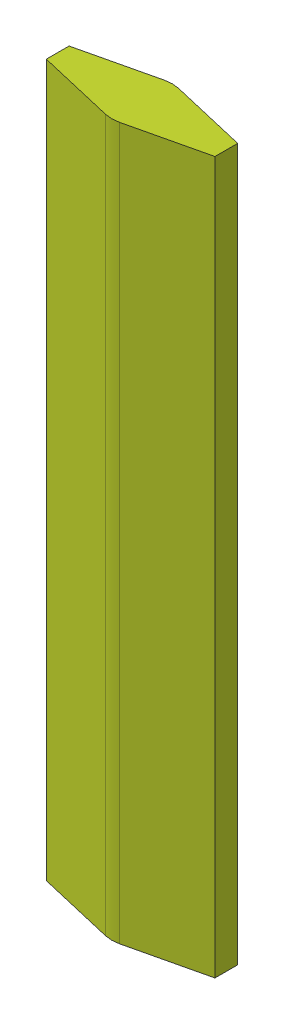
SolidWorks assembly RealString, configuration 默认. Lengths in mm.
Overall size (400 1620 359.66).
221 component instances, 7 part files, 3 mates.
Components (placement in the parent):
- RealUnit-1: RealUnit [默认] at (122.5675 -142.7262 804.774) size (400 106.44 359.66)
  - OuterShell-III-Part-6: OuterShell-III-Part [默认] at (-118.393 127.2935 -404.774) size (400 73.59 241.95)
  - OuterShell-III-Part-7: OuterShell-III-Part [默认] at (-118.393 127.2935 -404.774) x (-1 0 0) z (0 0 -1) size (400 73.59 241.95)
  - ConnectionRod-5: ConnectionRod [默认] at (-290.393 189.5608 -404.774) size (22.09 84 14)
  - ConnectionRod-9: ConnectionRod [默认] at (53.607 189.5608 -404.774) x (-1 0 0) z (0 0 -1) size (22.09 84 14)
  - InnerUnit-2: InnerUnit [默认] at (-116.4448 157.913 -484.774) x (-1 0 0) z (0 0 1) size (102 85 103.7)
    - BEGeDet-2: BEGeDet [默认] at (1.9481 14.6195 80) x (1 0 0) z (0 0 -1) size (80 40 80)
    - InnerShell-3: InnerShell [默认] at (1.9481 -36.3805 80) size (102 61 102)
    - Electronics-1: Electronics [默认] at (1.9481 24.7195 80) x (-1 0 0) z (0 0 1) size (21.21 85 103.7)
  - SiPMArray-1: SiPMArray [默认] at (46.607 162.6183 -404.774) size (10.4 81 40.4)
  - SiPMArray-2: SiPMArray [默认] at (-283.393 162.6183 -404.774) x (-1 0 0) z (0 0 -1) size (10.4 81 40.4)
- RealUnit-3: RealUnit [默认] at (122.5675 -66.7262 804.774) size (400 106.44 359.66)
  - OuterShell-III-Part-6: OuterShell-III-Part [默认] at (-118.393 127.2935 -404.774) size (400 73.59 241.95)
  - OuterShell-III-Part-7: OuterShell-III-Part [默认] at (-118.393 127.2935 -404.774) x (-1 0 0) z (0 0 -1) size (400 73.59 241.95)
  - ConnectionRod-5: ConnectionRod [默认] at (-290.393 189.5608 -404.774) size (22.09 84 14)
  - ConnectionRod-9: ConnectionRod [默认] at (53.607 189.5608 -404.774) x (-1 0 0) z (0 0 -1) size (22.09 84 14)
  - InnerUnit-2: InnerUnit [默认] at (-116.4448 157.913 -484.774) x (-1 0 0) z (0 0 1) size (102 85 103.7)
    - BEGeDet-2: BEGeDet [默认] at (1.9481 14.6195 80) x (1 0 0) z (0 0 -1) size (80 40 80)
    - InnerShell-3: InnerShell [默认] at (1.9481 -36.3805 80) size (102 61 102)
    - Electronics-1: Electronics [默认] at (1.9481 24.7195 80) x (-1 0 0) z (0 0 1) size (21.21 85 103.7)
  - SiPMArray-1: SiPMArray [默认] at (46.607 162.6183 -404.774) size (10.4 81 40.4)
  - SiPMArray-2: SiPMArray [默认] at (-283.393 162.6183 -404.774) x (-1 0 0) z (0 0 -1) size (10.4 81 40.4)
- RealUnit-22: RealUnit [默认] at (122.5675 9.2738 804.774) size (400 106.44 359.66)
  - OuterShell-III-Part-6: OuterShell-III-Part [默认] at (-118.393 127.2935 -404.774) size (400 73.59 241.95)
  - OuterShell-III-Part-7: OuterShell-III-Part [默认] at (-118.393 127.2935 -404.774) x (-1 0 0) z (0 0 -1) size (400 73.59 241.95)
  - ConnectionRod-5: ConnectionRod [默认] at (-290.393 189.5608 -404.774) size (22.09 84 14)
  - ConnectionRod-9: ConnectionRod [默认] at (53.607 189.5608 -404.774) x (-1 0 0) z (0 0 -1) size (22.09 84 14)
  - InnerUnit-2: InnerUnit [默认] at (-116.4448 157.913 -484.774) x (-1 0 0) z (0 0 1) size (102 85 103.7)
    - BEGeDet-2: BEGeDet [默认] at (1.9481 14.6195 80) x (1 0 0) z (0 0 -1) size (80 40 80)
    - InnerShell-3: InnerShell [默认] at (1.9481 -36.3805 80) size (102 61 102)
    - Electronics-1: Electronics [默认] at (1.9481 24.7195 80) x (-1 0 0) z (0 0 1) size (21.21 85 103.7)
  - SiPMArray-1: SiPMArray [默认] at (46.607 162.6183 -404.774) size (10.4 81 40.4)
  - SiPMArray-2: SiPMArray [默认] at (-283.393 162.6183 -404.774) x (-1 0 0) z (0 0 -1) size (10.4 81 40.4)
- RealUnit-23: RealUnit [默认] at (122.5675 85.2738 804.774) size (400 106.44 359.66)
  - OuterShell-III-Part-6: OuterShell-III-Part [默认] at (-118.393 127.2935 -404.774) size (400 73.59 241.95)
  - OuterShell-III-Part-7: OuterShell-III-Part [默认] at (-118.393 127.2935 -404.774) x (-1 0 0) z (0 0 -1) size (400 73.59 241.95)
  - ConnectionRod-5: ConnectionRod [默认] at (-290.393 189.5608 -404.774) size (22.09 84 14)
  - ConnectionRod-9: ConnectionRod [默认] at (53.607 189.5608 -404.774) x (-1 0 0) z (0 0 -1) size (22.09 84 14)
  - InnerUnit-2: InnerUnit [默认] at (-116.4448 157.913 -484.774) x (-1 0 0) z (0 0 1) size (102 85 103.7)
    - BEGeDet-2: BEGeDet [默认] at (1.9481 14.6195 80) x (1 0 0) z (0 0 -1) size (80 40 80)
    - InnerShell-3: InnerShell [默认] at (1.9481 -36.3805 80) size (102 61 102)
    - Electronics-1: Electronics [默认] at (1.9481 24.7195 80) x (-1 0 0) z (0 0 1) size (21.21 85 103.7)
  - SiPMArray-1: SiPMArray [默认] at (46.607 162.6183 -404.774) size (10.4 81 40.4)
  - SiPMArray-2: SiPMArray [默认] at (-283.393 162.6183 -404.774) x (-1 0 0) z (0 0 -1) size (10.4 81 40.4)
- RealUnit-24: RealUnit [默认] at (122.5675 161.2738 804.774) size (400 106.44 359.66)
  - OuterShell-III-Part-6: OuterShell-III-Part [默认] at (-118.393 127.2935 -404.774) size (400 73.59 241.95)
  - OuterShell-III-Part-7: OuterShell-III-Part [默认] at (-118.393 127.2935 -404.774) x (-1 0 0) z (0 0 -1) size (400 73.59 241.95)
  - ConnectionRod-5: ConnectionRod [默认] at (-290.393 189.5608 -404.774) size (22.09 84 14)
  - ConnectionRod-9: ConnectionRod [默认] at (53.607 189.5608 -404.774) x (-1 0 0) z (0 0 -1) size (22.09 84 14)
  - InnerUnit-2: InnerUnit [默认] at (-116.4448 157.913 -484.774) x (-1 0 0) z (0 0 1) size (102 85 103.7)
    - BEGeDet-2: BEGeDet [默认] at (1.9481 14.6195 80) x (1 0 0) z (0 0 -1) size (80 40 80)
    - InnerShell-3: InnerShell [默认] at (1.9481 -36.3805 80) size (102 61 102)
    - Electronics-1: Electronics [默认] at (1.9481 24.7195 80) x (-1 0 0) z (0 0 1) size (21.21 85 103.7)
  - SiPMArray-1: SiPMArray [默认] at (46.607 162.6183 -404.774) size (10.4 81 40.4)
  - SiPMArray-2: SiPMArray [默认] at (-283.393 162.6183 -404.774) x (-1 0 0) z (0 0 -1) size (10.4 81 40.4)
- RealUnit-25: RealUnit [默认] at (122.5675 237.2738 804.774) size (400 106.44 359.66)
  - OuterShell-III-Part-6: OuterShell-III-Part [默认] at (-118.393 127.2935 -404.774) size (400 73.59 241.95)
  - OuterShell-III-Part-7: OuterShell-III-Part [默认] at (-118.393 127.2935 -404.774) x (-1 0 0) z (0 0 -1) size (400 73.59 241.95)
  - ConnectionRod-5: ConnectionRod [默认] at (-290.393 189.5608 -404.774) size (22.09 84 14)
  - ConnectionRod-9: ConnectionRod [默认] at (53.607 189.5608 -404.774) x (-1 0 0) z (0 0 -1) size (22.09 84 14)
  - InnerUnit-2: InnerUnit [默认] at (-116.4448 157.913 -484.774) x (-1 0 0) z (0 0 1) size (102 85 103.7)
    - BEGeDet-2: BEGeDet [默认] at (1.9481 14.6195 80) x (1 0 0) z (0 0 -1) size (80 40 80)
    - InnerShell-3: InnerShell [默认] at (1.9481 -36.3805 80) size (102 61 102)
    - Electronics-1: Electronics [默认] at (1.9481 24.7195 80) x (-1 0 0) z (0 0 1) size (21.21 85 103.7)
  - SiPMArray-1: SiPMArray [默认] at (46.607 162.6183 -404.774) size (10.4 81 40.4)
  - SiPMArray-2: SiPMArray [默认] at (-283.393 162.6183 -404.774) x (-1 0 0) z (0 0 -1) size (10.4 81 40.4)
- RealUnit-26: RealUnit [默认] at (122.5675 313.2738 804.774) size (400 106.44 359.66)
  - OuterShell-III-Part-6: OuterShell-III-Part [默认] at (-118.393 127.2935 -404.774) size (400 73.59 241.95)
  - OuterShell-III-Part-7: OuterShell-III-Part [默认] at (-118.393 127.2935 -404.774) x (-1 0 0) z (0 0 -1) size (400 73.59 241.95)
  - ConnectionRod-5: ConnectionRod [默认] at (-290.393 189.5608 -404.774) size (22.09 84 14)
  - ConnectionRod-9: ConnectionRod [默认] at (53.607 189.5608 -404.774) x (-1 0 0) z (0 0 -1) size (22.09 84 14)
  - InnerUnit-2: InnerUnit [默认] at (-116.4448 157.913 -484.774) x (-1 0 0) z (0 0 1) size (102 85 103.7)
    - BEGeDet-2: BEGeDet [默认] at (1.9481 14.6195 80) x (1 0 0) z (0 0 -1) size (80 40 80)
    - InnerShell-3: InnerShell [默认] at (1.9481 -36.3805 80) size (102 61 102)
    - Electronics-1: Electronics [默认] at (1.9481 24.7195 80) x (-1 0 0) z (0 0 1) size (21.21 85 103.7)
  - SiPMArray-1: SiPMArray [默认] at (46.607 162.6183 -404.774) size (10.4 81 40.4)
  - SiPMArray-2: SiPMArray [默认] at (-283.393 162.6183 -404.774) x (-1 0 0) z (0 0 -1) size (10.4 81 40.4)
- RealUnit-27: RealUnit [默认] at (122.5675 389.2738 804.774) size (400 106.44 359.66)
  - OuterShell-III-Part-6: OuterShell-III-Part [默认] at (-118.393 127.2935 -404.774) size (400 73.59 241.95)
  - OuterShell-III-Part-7: OuterShell-III-Part [默认] at (-118.393 127.2935 -404.774) x (-1 0 0) z (0 0 -1) size (400 73.59 241.95)
  - ConnectionRod-5: ConnectionRod [默认] at (-290.393 189.5608 -404.774) size (22.09 84 14)
  - ConnectionRod-9: ConnectionRod [默认] at (53.607 189.5608 -404.774) x (-1 0 0) z (0 0 -1) size (22.09 84 14)
  - InnerUnit-2: InnerUnit [默认] at (-116.4448 157.913 -484.774) x (-1 0 0) z (0 0 1) size (102 85 103.7)
    - BEGeDet-2: BEGeDet [默认] at (1.9481 14.6195 80) x (1 0 0) z (0 0 -1) size (80 40 80)
    - InnerShell-3: InnerShell [默认] at (1.9481 -36.3805 80) size (102 61 102)
    - Electronics-1: Electronics [默认] at (1.9481 24.7195 80) x (-1 0 0) z (0 0 1) size (21.21 85 103.7)
  - SiPMArray-1: SiPMArray [默认] at (46.607 162.6183 -404.774) size (10.4 81 40.4)
  - SiPMArray-2: SiPMArray [默认] at (-283.393 162.6183 -404.774) x (-1 0 0) z (0 0 -1) size (10.4 81 40.4)
- RealUnit-28: RealUnit [默认] at (122.5675 465.2738 804.774) size (400 106.44 359.66)
  - OuterShell-III-Part-6: OuterShell-III-Part [默认] at (-118.393 127.2935 -404.774) size (400 73.59 241.95)
  - OuterShell-III-Part-7: OuterShell-III-Part [默认] at (-118.393 127.2935 -404.774) x (-1 0 0) z (0 0 -1) size (400 73.59 241.95)
  - ConnectionRod-5: ConnectionRod [默认] at (-290.393 189.5608 -404.774) size (22.09 84 14)
  - ConnectionRod-9: ConnectionRod [默认] at (53.607 189.5608 -404.774) x (-1 0 0) z (0 0 -1) size (22.09 84 14)
  - InnerUnit-2: InnerUnit [默认] at (-116.4448 157.913 -484.774) x (-1 0 0) z (0 0 1) size (102 85 103.7)
    - BEGeDet-2: BEGeDet [默认] at (1.9481 14.6195 80) x (1 0 0) z (0 0 -1) size (80 40 80)
    - InnerShell-3: InnerShell [默认] at (1.9481 -36.3805 80) size (102 61 102)
    - Electronics-1: Electronics [默认] at (1.9481 24.7195 80) x (-1 0 0) z (0 0 1) size (21.21 85 103.7)
  - SiPMArray-1: SiPMArray [默认] at (46.607 162.6183 -404.774) size (10.4 81 40.4)
  - SiPMArray-2: SiPMArray [默认] at (-283.393 162.6183 -404.774) x (-1 0 0) z (0 0 -1) size (10.4 81 40.4)
- RealUnit-29: RealUnit [默认] at (122.5675 541.2738 804.774) size (400 106.44 359.66)
  - OuterShell-III-Part-6: OuterShell-III-Part [默认] at (-118.393 127.2935 -404.774) size (400 73.59 241.95)
  - OuterShell-III-Part-7: OuterShell-III-Part [默认] at (-118.393 127.2935 -404.774) x (-1 0 0) z (0 0 -1) size (400 73.59 241.95)
  - ConnectionRod-5: ConnectionRod [默认] at (-290.393 189.5608 -404.774) size (22.09 84 14)
  - ConnectionRod-9: ConnectionRod [默认] at (53.607 189.5608 -404.774) x (-1 0 0) z (0 0 -1) size (22.09 84 14)
  - InnerUnit-2: InnerUnit [默认] at (-116.4448 157.913 -484.774) x (-1 0 0) z (0 0 1) size (102 85 103.7)
    - BEGeDet-2: BEGeDet [默认] at (1.9481 14.6195 80) x (1 0 0) z (0 0 -1) size (80 40 80)
    - InnerShell-3: InnerShell [默认] at (1.9481 -36.3805 80) size (102 61 102)
    - Electronics-1: Electronics [默认] at (1.9481 24.7195 80) x (-1 0 0) z (0 0 1) size (21.21 85 103.7)
  - SiPMArray-1: SiPMArray [默认] at (46.607 162.6183 -404.774) size (10.4 81 40.4)
  - SiPMArray-2: SiPMArray [默认] at (-283.393 162.6183 -404.774) x (-1 0 0) z (0 0 -1) size (10.4 81 40.4)
- RealUnit-30: RealUnit [默认] at (122.5675 617.2738 804.774) size (400 106.44 359.66)
  - OuterShell-III-Part-6: OuterShell-III-Part [默认] at (-118.393 127.2935 -404.774) size (400 73.59 241.95)
  - OuterShell-III-Part-7: OuterShell-III-Part [默认] at (-118.393 127.2935 -404.774) x (-1 0 0) z (0 0 -1) size (400 73.59 241.95)
  - ConnectionRod-5: ConnectionRod [默认] at (-290.393 189.5608 -404.774) size (22.09 84 14)
  - ConnectionRod-9: ConnectionRod [默认] at (53.607 189.5608 -404.774) x (-1 0 0) z (0 0 -1) size (22.09 84 14)
  - InnerUnit-2: InnerUnit [默认] at (-116.4448 157.913 -484.774) x (-1 0 0) z (0 0 1) size (102 85 103.7)
    - BEGeDet-2: BEGeDet [默认] at (1.9481 14.6195 80) x (1 0 0) z (0 0 -1) size (80 40 80)
    - InnerShell-3: InnerShell [默认] at (1.9481 -36.3805 80) size (102 61 102)
    - Electronics-1: Electronics [默认] at (1.9481 24.7195 80) x (-1 0 0) z (0 0 1) size (21.21 85 103.7)
  - SiPMArray-1: SiPMArray [默认] at (46.607 162.6183 -404.774) size (10.4 81 40.4)
  - SiPMArray-2: SiPMArray [默认] at (-283.393 162.6183 -404.774) x (-1 0 0) z (0 0 -1) size (10.4 81 40.4)
- RealUnit-31: RealUnit [默认] at (122.5675 693.2738 804.774) size (400 106.44 359.66)
  - OuterShell-III-Part-6: OuterShell-III-Part [默认] at (-118.393 127.2935 -404.774) size (400 73.59 241.95)
  - OuterShell-III-Part-7: OuterShell-III-Part [默认] at (-118.393 127.2935 -404.774) x (-1 0 0) z (0 0 -1) size (400 73.59 241.95)
  - ConnectionRod-5: ConnectionRod [默认] at (-290.393 189.5608 -404.774) size (22.09 84 14)
  - ConnectionRod-9: ConnectionRod [默认] at (53.607 189.5608 -404.774) x (-1 0 0) z (0 0 -1) size (22.09 84 14)
  - InnerUnit-2: InnerUnit [默认] at (-116.4448 157.913 -484.774) x (-1 0 0) z (0 0 1) size (102 85 103.7)
    - BEGeDet-2: BEGeDet [默认] at (1.9481 14.6195 80) x (1 0 0) z (0 0 -1) size (80 40 80)
    - InnerShell-3: InnerShell [默认] at (1.9481 -36.3805 80) size (102 61 102)
    - Electronics-1: Electronics [默认] at (1.9481 24.7195 80) x (-1 0 0) z (0 0 1) size (21.21 85 103.7)
  - SiPMArray-1: SiPMArray [默认] at (46.607 162.6183 -404.774) size (10.4 81 40.4)
  - SiPMArray-2: SiPMArray [默认] at (-283.393 162.6183 -404.774) x (-1 0 0) z (0 0 -1) size (10.4 81 40.4)
- RealUnit-32: RealUnit [默认] at (122.5675 769.2738 804.774) size (400 106.44 359.66)
  - OuterShell-III-Part-6: OuterShell-III-Part [默认] at (-118.393 127.2935 -404.774) size (400 73.59 241.95)
  - OuterShell-III-Part-7: OuterShell-III-Part [默认] at (-118.393 127.2935 -404.774) x (-1 0 0) z (0 0 -1) size (400 73.59 241.95)
  - ConnectionRod-5: ConnectionRod [默认] at (-290.393 189.5608 -404.774) size (22.09 84 14)
  - ConnectionRod-9: ConnectionRod [默认] at (53.607 189.5608 -404.774) x (-1 0 0) z (0 0 -1) size (22.09 84 14)
  - InnerUnit-2: InnerUnit [默认] at (-116.4448 157.913 -484.774) x (-1 0 0) z (0 0 1) size (102 85 103.7)
    - BEGeDet-2: BEGeDet [默认] at (1.9481 14.6195 80) x (1 0 0) z (0 0 -1) size (80 40 80)
    - InnerShell-3: InnerShell [默认] at (1.9481 -36.3805 80) size (102 61 102)
    - Electronics-1: Electronics [默认] at (1.9481 24.7195 80) x (-1 0 0) z (0 0 1) size (21.21 85 103.7)
  - SiPMArray-1: SiPMArray [默认] at (46.607 162.6183 -404.774) size (10.4 81 40.4)
  - SiPMArray-2: SiPMArray [默认] at (-283.393 162.6183 -404.774) x (-1 0 0) z (0 0 -1) size (10.4 81 40.4)
- RealUnit-33: RealUnit [默认] at (122.5675 845.2738 804.774) size (400 106.44 359.66)
  - OuterShell-III-Part-6: OuterShell-III-Part [默认] at (-118.393 127.2935 -404.774) size (400 73.59 241.95)
  - OuterShell-III-Part-7: OuterShell-III-Part [默认] at (-118.393 127.2935 -404.774) x (-1 0 0) z (0 0 -1) size (400 73.59 241.95)
  - ConnectionRod-5: ConnectionRod [默认] at (-290.393 189.5608 -404.774) size (22.09 84 14)
  - ConnectionRod-9: ConnectionRod [默认] at (53.607 189.5608 -404.774) x (-1 0 0) z (0 0 -1) size (22.09 84 14)
  - InnerUnit-2: InnerUnit [默认] at (-116.4448 157.913 -484.774) x (-1 0 0) z (0 0 1) size (102 85 103.7)
    - BEGeDet-2: BEGeDet [默认] at (1.9481 14.6195 80) x (1 0 0) z (0 0 -1) size (80 40 80)
    - InnerShell-3: InnerShell [默认] at (1.9481 -36.3805 80) size (102 61 102)
    - Electronics-1: Electronics [默认] at (1.9481 24.7195 80) x (-1 0 0) z (0 0 1) size (21.21 85 103.7)
  - SiPMArray-1: SiPMArray [默认] at (46.607 162.6183 -404.774) size (10.4 81 40.4)
  - SiPMArray-2: SiPMArray [默认] at (-283.393 162.6183 -404.774) x (-1 0 0) z (0 0 -1) size (10.4 81 40.4)
- RealUnit-34: RealUnit [默认] at (122.5675 921.2738 804.774) size (400 106.44 359.66)
  - OuterShell-III-Part-6: OuterShell-III-Part [默认] at (-118.393 127.2935 -404.774) size (400 73.59 241.95)
  - OuterShell-III-Part-7: OuterShell-III-Part [默认] at (-118.393 127.2935 -404.774) x (-1 0 0) z (0 0 -1) size (400 73.59 241.95)
  - ConnectionRod-5: ConnectionRod [默认] at (-290.393 189.5608 -404.774) size (22.09 84 14)
  - ConnectionRod-9: ConnectionRod [默认] at (53.607 189.5608 -404.774) x (-1 0 0) z (0 0 -1) size (22.09 84 14)
  - InnerUnit-2: InnerUnit [默认] at (-116.4448 157.913 -484.774) x (-1 0 0) z (0 0 1) size (102 85 103.7)
    - BEGeDet-2: BEGeDet [默认] at (1.9481 14.6195 80) x (1 0 0) z (0 0 -1) size (80 40 80)
    - InnerShell-3: InnerShell [默认] at (1.9481 -36.3805 80) size (102 61 102)
    - Electronics-1: Electronics [默认] at (1.9481 24.7195 80) x (-1 0 0) z (0 0 1) size (21.21 85 103.7)
  - SiPMArray-1: SiPMArray [默认] at (46.607 162.6183 -404.774) size (10.4 81 40.4)
  - SiPMArray-2: SiPMArray [默认] at (-283.393 162.6183 -404.774) x (-1 0 0) z (0 0 -1) size (10.4 81 40.4)
- RealUnit-35: RealUnit [默认] at (122.5675 997.2738 804.774) size (400 106.44 359.66)
  - OuterShell-III-Part-6: OuterShell-III-Part [默认] at (-118.393 127.2935 -404.774) size (400 73.59 241.95)
  - OuterShell-III-Part-7: OuterShell-III-Part [默认] at (-118.393 127.2935 -404.774) x (-1 0 0) z (0 0 -1) size (400 73.59 241.95)
  - ConnectionRod-5: ConnectionRod [默认] at (-290.393 189.5608 -404.774) size (22.09 84 14)
  - ConnectionRod-9: ConnectionRod [默认] at (53.607 189.5608 -404.774) x (-1 0 0) z (0 0 -1) size (22.09 84 14)
  - InnerUnit-2: InnerUnit [默认] at (-116.4448 157.913 -484.774) x (-1 0 0) z (0 0 1) size (102 85 103.7)
    - BEGeDet-2: BEGeDet [默认] at (1.9481 14.6195 80) x (1 0 0) z (0 0 -1) size (80 40 80)
    - InnerShell-3: InnerShell [默认] at (1.9481 -36.3805 80) size (102 61 102)
    - Electronics-1: Electronics [默认] at (1.9481 24.7195 80) x (-1 0 0) z (0 0 1) size (21.21 85 103.7)
  - SiPMArray-1: SiPMArray [默认] at (46.607 162.6183 -404.774) size (10.4 81 40.4)
  - SiPMArray-2: SiPMArray [默认] at (-283.393 162.6183 -404.774) x (-1 0 0) z (0 0 -1) size (10.4 81 40.4)
- RealUnit-36: RealUnit [默认] at (122.5675 1073.2738 804.774) size (400 106.44 359.66)
  - OuterShell-III-Part-6: OuterShell-III-Part [默认] at (-118.393 127.2935 -404.774) size (400 73.59 241.95)
  - OuterShell-III-Part-7: OuterShell-III-Part [默认] at (-118.393 127.2935 -404.774) x (-1 0 0) z (0 0 -1) size (400 73.59 241.95)
  - ConnectionRod-5: ConnectionRod [默认] at (-290.393 189.5608 -404.774) size (22.09 84 14)
  - ConnectionRod-9: ConnectionRod [默认] at (53.607 189.5608 -404.774) x (-1 0 0) z (0 0 -1) size (22.09 84 14)
  - InnerUnit-2: InnerUnit [默认] at (-116.4448 157.913 -484.774) x (-1 0 0) z (0 0 1) size (102 85 103.7)
    - BEGeDet-2: BEGeDet [默认] at (1.9481 14.6195 80) x (1 0 0) z (0 0 -1) size (80 40 80)
    - InnerShell-3: InnerShell [默认] at (1.9481 -36.3805 80) size (102 61 102)
    - Electronics-1: Electronics [默认] at (1.9481 24.7195 80) x (-1 0 0) z (0 0 1) size (21.21 85 103.7)
  - SiPMArray-1: SiPMArray [默认] at (46.607 162.6183 -404.774) size (10.4 81 40.4)
  - SiPMArray-2: SiPMArray [默认] at (-283.393 162.6183 -404.774) x (-1 0 0) z (0 0 -1) size (10.4 81 40.4)
- RealUnit-37: RealUnit [默认] at (122.5675 1149.2738 804.774) size (400 106.44 359.66)
  - OuterShell-III-Part-6: OuterShell-III-Part [默认] at (-118.393 127.2935 -404.774) size (400 73.59 241.95)
  - OuterShell-III-Part-7: OuterShell-III-Part [默认] at (-118.393 127.2935 -404.774) x (-1 0 0) z (0 0 -1) size (400 73.59 241.95)
  - ConnectionRod-5: ConnectionRod [默认] at (-290.393 189.5608 -404.774) size (22.09 84 14)
  - ConnectionRod-9: ConnectionRod [默认] at (53.607 189.5608 -404.774) x (-1 0 0) z (0 0 -1) size (22.09 84 14)
  - InnerUnit-2: InnerUnit [默认] at (-116.4448 157.913 -484.774) x (-1 0 0) z (0 0 1) size (102 85 103.7)
    - BEGeDet-2: BEGeDet [默认] at (1.9481 14.6195 80) x (1 0 0) z (0 0 -1) size (80 40 80)
    - InnerShell-3: InnerShell [默认] at (1.9481 -36.3805 80) size (102 61 102)
    - Electronics-1: Electronics [默认] at (1.9481 24.7195 80) x (-1 0 0) z (0 0 1) size (21.21 85 103.7)
  - SiPMArray-1: SiPMArray [默认] at (46.607 162.6183 -404.774) size (10.4 81 40.4)
  - SiPMArray-2: SiPMArray [默认] at (-283.393 162.6183 -404.774) x (-1 0 0) z (0 0 -1) size (10.4 81 40.4)
- RealUnit-38: RealUnit [默认] at (122.5675 1225.2738 804.774) size (400 106.44 359.66)
  - OuterShell-III-Part-6: OuterShell-III-Part [默认] at (-118.393 127.2935 -404.774) size (400 73.59 241.95)
  - OuterShell-III-Part-7: OuterShell-III-Part [默认] at (-118.393 127.2935 -404.774) x (-1 0 0) z (0 0 -1) size (400 73.59 241.95)
  - ConnectionRod-5: ConnectionRod [默认] at (-290.393 189.5608 -404.774) size (22.09 84 14)
  - ConnectionRod-9: ConnectionRod [默认] at (53.607 189.5608 -404.774) x (-1 0 0) z (0 0 -1) size (22.09 84 14)
  - InnerUnit-2: InnerUnit [默认] at (-116.4448 157.913 -484.774) x (-1 0 0) z (0 0 1) size (102 85 103.7)
    - BEGeDet-2: BEGeDet [默认] at (1.9481 14.6195 80) x (1 0 0) z (0 0 -1) size (80 40 80)
    - InnerShell-3: InnerShell [默认] at (1.9481 -36.3805 80) size (102 61 102)
    - Electronics-1: Electronics [默认] at (1.9481 24.7195 80) x (-1 0 0) z (0 0 1) size (21.21 85 103.7)
  - SiPMArray-1: SiPMArray [默认] at (46.607 162.6183 -404.774) size (10.4 81 40.4)
  - SiPMArray-2: SiPMArray [默认] at (-283.393 162.6183 -404.774) x (-1 0 0) z (0 0 -1) size (10.4 81 40.4)
- RealUnit-39: RealUnit [默认] at (122.5675 1301.2738 804.774) size (400 106.44 359.66)
  - OuterShell-III-Part-6: OuterShell-III-Part [默认] at (-118.393 127.2935 -404.774) size (400 73.59 241.95)
  - OuterShell-III-Part-7: OuterShell-III-Part [默认] at (-118.393 127.2935 -404.774) x (-1 0 0) z (0 0 -1) size (400 73.59 241.95)
  - ConnectionRod-5: ConnectionRod [默认] at (-290.393 189.5608 -404.774) size (22.09 84 14)
  - ConnectionRod-9: ConnectionRod [默认] at (53.607 189.5608 -404.774) x (-1 0 0) z (0 0 -1) size (22.09 84 14)
  - InnerUnit-2: InnerUnit [默认] at (-116.4448 157.913 -484.774) x (-1 0 0) z (0 0 1) size (102 85 103.7)
    - BEGeDet-2: BEGeDet [默认] at (1.9481 14.6195 80) x (1 0 0) z (0 0 -1) size (80 40 80)
    - InnerShell-3: InnerShell [默认] at (1.9481 -36.3805 80) size (102 61 102)
    - Electronics-1: Electronics [默认] at (1.9481 24.7195 80) x (-1 0 0) z (0 0 1) size (21.21 85 103.7)
  - SiPMArray-1: SiPMArray [默认] at (46.607 162.6183 -404.774) size (10.4 81 40.4)
  - SiPMArray-2: SiPMArray [默认] at (-283.393 162.6183 -404.774) x (-1 0 0) z (0 0 -1) size (10.4 81 40.4)
- RealStringBox-III-2: RealStringBox-III [默认] at (4.1746 -15.4326 400) size (384 1620 138)
Mates (geometry in assembly coordinates):
- 重合5: coincident anti-aligned: plane of RealUnit-1/OuterShell-III-Part-6 through (4.1746 -15.4326 400) normal (0 -1 0); plane of RealStringBox-III-2 through (4.1746 -15.4326 400) normal (0 1 0)
- 同心2: concentric anti-aligned: circle of RealUnit-39/OuterShell-III-Part-6; circle of RealStringBox-III-2
- 平行2: parallel anti-aligned: line of RealUnit-39/SiPMArray-2 through (-160.8254 1480.0921 399.8) axis (0 0 -1); line of RealStringBox-III-2 through (-177.8254 1584.5674 382.0225) axis (0 0 1)
